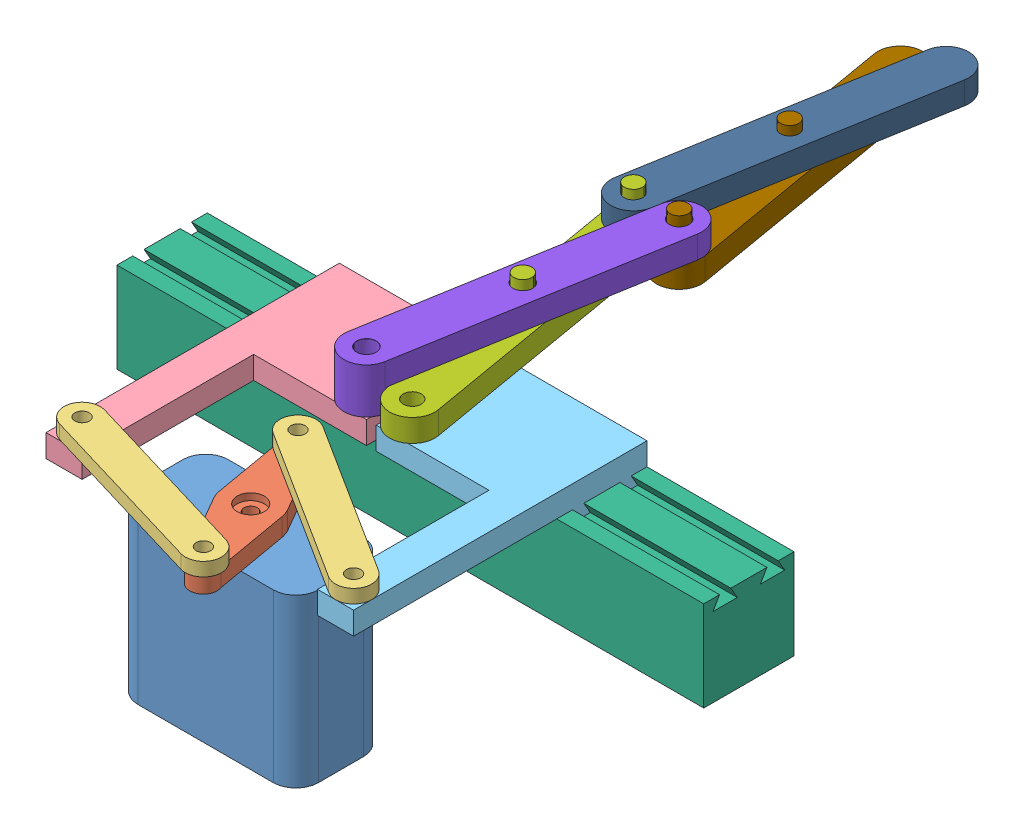
SolidWorks assembly simcut2, configuration Default. Lengths in mm.
Overall size (130 53 178.47).
11 component instances, 10 part files, 27 mates.
Components (placement in the parent):
- servo2-1: servo2 [Default] at (17.0411 4.9952 27.8093) size (40 37 20)
- servoclose.cut-1: servoclose.cut [Default] at (17.0411 45.9952 27.8093) x (0.939983 0 -0.341221) z (0 1 0) size (12 41 10)
- servolink.cut-1: servolink.cut [Default] at (44.8323 48.9952 32.8093) x (0.536243 0 -0.844064) z (0 1 0) size (8 48 3)
- servolink.cut-2: servolink.cut [Default] at (-15.3138 48.9952 32.8093) x (-0.286243 0 0.958157) z (0 1 0) size (8 48 3)
- armleft2-1: armleft2 [Default] at (-2.8138 40.9952 1.8093) size (33 7.5 65)
- armright2-1: armright2 [Default] at (32.3323 40.9952 1.8093) size (33 7.5 65)
- base3-1: base3 [Default] at (16.4082 30.9952 -18.1907) size (130 20 20)
- 2stick.cut-1: 2stick.cut [Default] at (19.8323 50.9952 -5.1907) x (0.985599 0 -0.169102) z (0 1 0) size (10 70 12)
- 3hold.cut-1: 3hold.cut [Default] at (9.6862 50.9952 -5.1907) x (0.985599 0 0.169102) z (0 1 0) size (10 70 10)
- 2sticknh.cut-1: 2sticknh.cut [Default] at (19.8323 50.9952 -64.3266) x (0.985599 0 -0.169102) z (0 1 0) size (10 70 12)
- 2hold.cut-1: 2hold.cut [Default] at (14.7592 50.9952 -93.8946) x (0.169102 0 -0.985599) z (0.985599 0 0.169102) size (70 5 10)
Mates (geometry in assembly coordinates):
- Concentric1: concentric: cylinder of servo2-1 through (17.0411 36.9952 27.8093) axis (0 1 0) radius 3; cylinder of servoclose.cut-1 through (17.0411 40.9952 27.8093) axis (0 -1 0) radius 3
- Coincident2: coincident: plane of servo2-1 through (17.0411 41.9952 27.8093) normal (0 1 0); plane of servoclose.cut-1 through (32.3615 41.9952 19.3513) normal (0 -1 0)
- Coincident3: coincident: plane of servoclose.cut-1 through (32.3615 45.9952 19.3513) normal (0 1 0); plane of servolink.cut-2 through (-37.3748 45.9952 27.8093) normal (0 -1 0)
- Coincident4: coincident: plane of servoclose.cut-1 through (32.3615 45.9952 19.3513) normal (0 1 0); plane of servolink.cut-1 through (71.457 45.9952 27.8093) normal (0 -1 0)
- Coincident5: coincident: plane of servolink.cut-1 through (71.457 45.9952 27.8093) normal (0 -1 0); plane of armright2-1 through (58.957 45.9952 1.8093) normal (0 1 0)
- Coincident6: coincident: plane of servolink.cut-2 through (-37.3748 45.9952 27.8093) normal (0 -1 0); plane of armleft2-1 through (-24.8748 45.9952 1.8093) normal (0 1 0)
- Coincident8: coincident: plane of armright2-1 through (75.457 38.4952 1.8093) normal (0 -1 0); plane of base3-1 through (82.215 38.4952 -18.1907) normal (0 1 0)
- Coincident9: coincident: line of armright2-1 through (75.457 38.4952 -10.2474) axis (-1 0 0); line of base3-1 through (82.215 38.4952 -10.2474) axis (-1 0 0)
- Coincident11: coincident: plane of armleft2-1 through (-24.8748 40.9952 1.8093) normal (0 -1 0); plane of base3-1 through (82.215 40.9952 -18.1907) normal (0 1 0)
- Coincident12: coincident: line of armleft2-1 through (-41.3748 38.4952 -26.1341) axis (1 0 0); line of base3-1 through (82.215 38.4952 -26.1341) axis (-1 0 0)
- Coincident13: coincident: plane of assembly through (17.0411 4.9952 -8.1907) normal (0 0 1); plane of base3-1 through (82.215 30.9952 -8.1907) normal (0 0 1); plane of assembly
- Coincident20: coincident: plane of armright2-1 through (58.957 45.9952 1.8093) normal (0 1 0); plane of 2stick.cut-1 through (46.457 45.9952 -12.1907) normal (0 -1 0)
- Coincident21: coincident: plane of armleft2-1 through (-24.8748 45.9952 1.8093) normal (0 1 0); plane of 3hold.cut-1 through (-12.3748 45.9952 -12.1907) normal (0 -1 0)
- Concentric16: concentric: cylinder of 2stick.cut-1 through (17.0411 57.9952 -18.0817) axis (0 -1 0) radius 2; cylinder of 3hold.cut-1 through (17.0411 55.9952 -18.0817) axis (0 1 0) radius 2.15
- LimitDistance3: limit distance = 1 mm: plane of armleft2-1 through (13.6862 45.9952 1.8093) normal (1 0 0); plane of armright2-1 through (15.8323 45.9952 -8.1907) normal (-1 0 0)
- Concentric23: concentric: cylinder of 3hold.cut-1 through (46.457 55.9952 -23.9726) axis (0 1 0) radius 2.15; cylinder of 2sticknh.cut-1 through (46.457 57.9952 -23.9726) axis (0 -1 0) radius 2
- Coincident26: coincident: plane of 3hold.cut-1 through (-12.3748 50.9952 -12.1907) normal (0 -1 0); plane of 2sticknh.cut-1 through (46.457 50.9952 -23.9726) normal (0 1 0)
- Concentric24: concentric: cylinder of 2stick.cut-1 through (-12.3748 57.9952 -23.9726) axis (0 -1 0) radius 2; cylinder of 2hold.cut-1 through (-12.3748 55.9952 -23.9726) axis (0 1 0) radius 2
- Concentric25: concentric anti-aligned: cylinder of 2sticknh.cut-1 through (17.0411 57.9952 -29.8635) axis (0 -1 0) radius 2; cylinder of 2hold.cut-1 through (17.0411 55.9952 -29.8635) axis (0 1 0) radius 2
- Coincident27: coincident: plane of 2sticknh.cut-1 through (46.457 50.9952 -23.9726) normal (0 1 0); plane of 2hold.cut-1 through (-12.3748 50.9952 -23.9726) normal (0 -1 0)
- LimitDistance4: limit distance = 0 mm: plane of 3hold.cut-1 through (4.7582 55.9952 -6.0362) normal (-0.985599 0 -0.169102); plane of 2hold.cut-1 through (14.6142 55.9952 -63.4811) normal (0.985599 0 0.169102)
- Concentric26: concentric: cylinder of servoclose.cut-1 through (1.7207 35.9952 36.2672) axis (0 1 0) radius 1.6; cylinder of servolink.cut-2 through (1.7207 45.9952 36.2672) axis (0 1 0) radius 1.6
- Concentric27: concentric: cylinder of servoclose.cut-1 through (32.3615 35.9952 19.3513) axis (0 1 0) radius 1.6; cylinder of servolink.cut-1 through (32.3615 45.9952 19.3513) axis (0 1 0) radius 1.6
- Concentric28: concentric: cylinder of armleft2-1 through (-12.3748 40.9952 -5.1907) axis (0 1 0) radius 1.6; cylinder of 3hold.cut-1 through (-12.3748 55.9952 -12.1907) axis (0 1 0) radius 2.15
- Concentric29: concentric: cylinder of armright2-1 through (46.457 38.4952 -5.1907) axis (0 1 0) radius 1.6; cylinder of 2stick.cut-1 through (46.457 45.9952 -12.1907) axis (0 1 0) radius 2
- Concentric30: concentric: cylinder of servolink.cut-2 through (-37.3748 45.9952 27.8093) axis (0 1 0) radius 1.6; cylinder of armleft2-1 through (-37.3748 40.9952 32.8093) axis (0 1 0) radius 1.6
- Concentric31: concentric: cylinder of servolink.cut-1 through (71.457 45.9952 27.8093) axis (0 1 0) radius 1.6; cylinder of armright2-1 through (71.457 38.4952 32.8093) axis (0 1 0) radius 1.6
